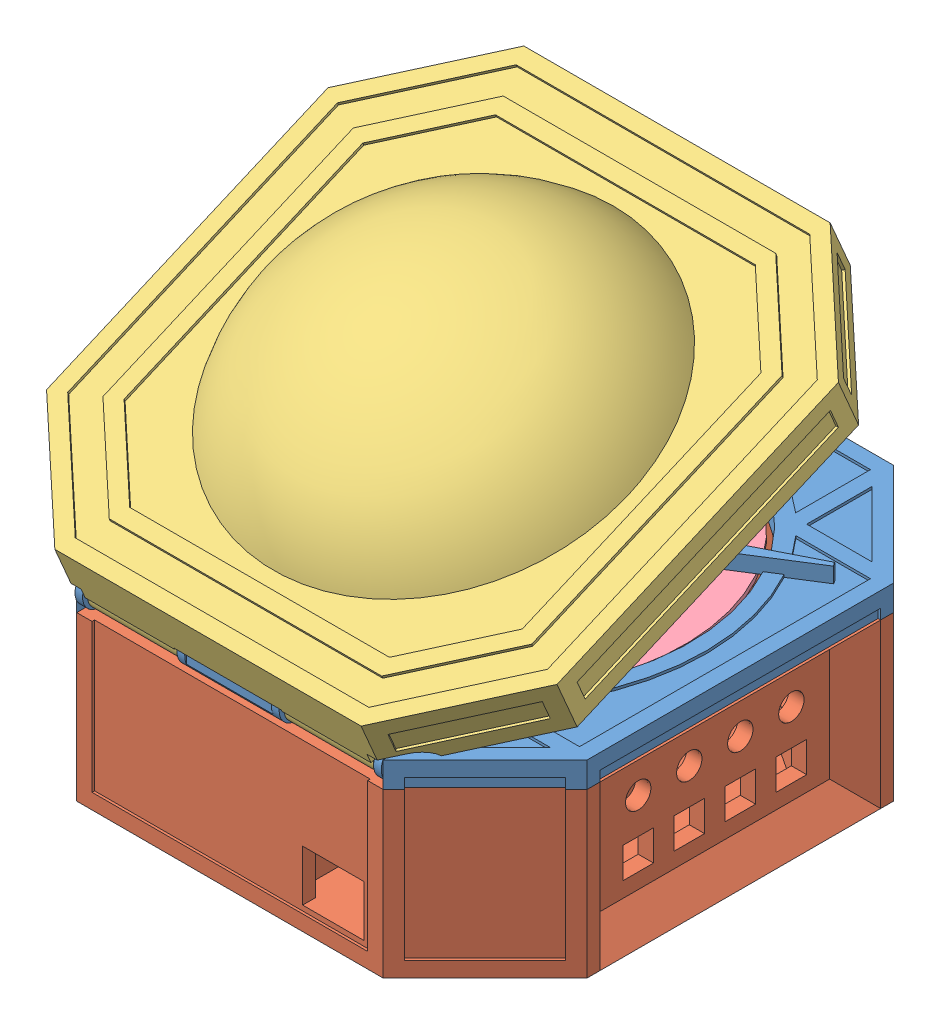
SolidWorks assembly Overall, configuration Default. Lengths in mm.
Overall size (445.09 104.23 565.56).
4 component instances, 4 part files, 7 mates.
Components (placement in the parent):
- Body_Lip_3_hinge-1: Body_Lip_3_hinge [Default] at (37.881 18.6997 117.2221) x (-1 0 0) z (0 0 -1) size (100 24.69 100.36)
- Compass_Base (2)-1: Compass_Base (2) [Default] at (-12.119 -12.8003 167.2221) size (100 37 100)
- Lid-3: Lid [Default] at (-12.119 42.6163 171.6242) x (1 0 0) z (0 0.918925 0.394431) size (100 100 36.01)
- face_with_gear-1: face_with_gear [Default] at (132.1488 14.1997 235.1366) x (-0.400561 0 -0.91627) z (0 1 0) size (544.46 247.75 9)
Mates (geometry in assembly coordinates):
- Coincident1: coincident anti-aligned: plane of Body_Lip_3_hinge-1 through (37.881 19.1997 117.2221) normal (0 -1 0); plane of Compass_Base (2)-1 through (-12.119 19.1997 167.2221) normal (0 1 0)
- Coincident4: coincident aligned: plane of Body_Lip_3_hinge-1 through (37.881 23.6997 117.2221) normal (0 0 -1); plane of Compass_Base (2)-1 through (-12.119 19.1997 117.2221) normal (0 0 -1)
- Coincident5: coincident aligned: plane of Body_Lip_3_hinge-1 through (-62.119 23.6997 117.2221) normal (-1 0 0); plane of Compass_Base (2)-1 through (-62.119 19.1997 167.2221) normal (-1 0 0)
- Concentric1: concentric aligned: cylinder of Body_Lip_3_hinge-1 through (-5.6545 22.6997 214.2221) axis (1 0 0) radius 1.25; cylinder of Lid-3 through (-1.619 22.6997 214.2221) axis (1 0 0) radius 1.65
- Distance1: distance = 0.5 mm anti-aligned: plane of Lid-3 through (15.881 42.6163 171.6242) normal (1 0 0); plane of Body_Lip_3_hinge-1 through (16.381 24.1997 217.2221) normal (-1 0 0)
- Concentric3: concentric aligned: cylinder of Compass_Base (2)-1 through (-12.119 24.1997 167.2221) axis (0 -1 0) radius 1.9; cylinder of face_with_gear-1 through (-12.119 22.6997 167.2221) axis (0 -1 0) radius 2
- Coincident6: coincident anti-aligned: plane of Compass_Base (2)-1 through (-12.119 14.1997 167.2221) normal (0 1 0); plane of face_with_gear-1 through (132.1488 14.1997 235.1366) normal (0 -1 0)
